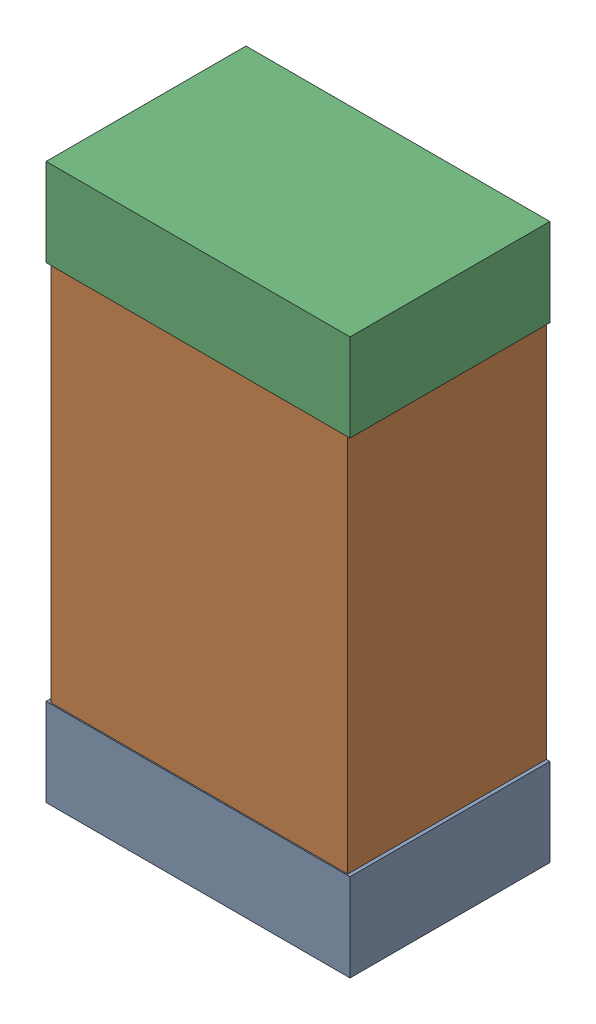
SolidWorks assembly C8Kanaloa_v2.0.0_Motor, configuration Default. Lengths in mm.
Overall size (1.3 2.38 0.85).
6 component instances, 2 part files, 0 mates.
Components (placement in the parent):
- 330415056-1: 330415056 [Default] at (112.268 109.803 0) size (1.3 0.38 0.85)
  - Extruded_2-1: Extruded_2 [Default] at origin size (1.3 0.38 0.85)
- 352877008-1: 352877008 [Default] at (112.268 110.803 0) size (1.27 2.2 0.85)
  - Extruded_3-1: Extruded_3 [Default] at origin size (1.27 2.2 0.85)
- 330415056-2: 330415056 [Default] at (112.268 111.803 0) size (1.3 0.38 0.85)
  - Extruded_2-1: Extruded_2 [Default] at origin size (1.3 0.38 0.85)
